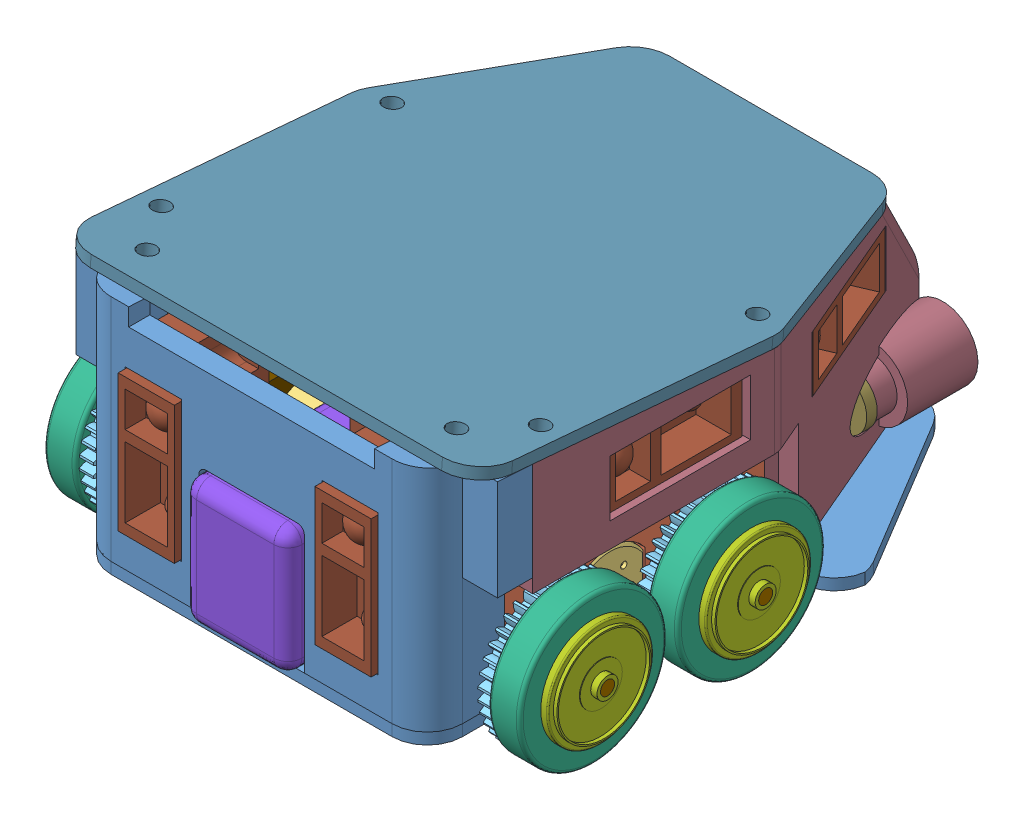
SolidWorks assembly Assem1, configuration Default. Lengths in mm.
Overall size (71.71 43.6 82.34).
50 component instances, 20 part files, 118 mates.
Components (placement in the parent):
- PCB-1: PCB [Default] at (41.0983 40.4465 84.0806) size (69.9 1.6 78)
- Ga DC2-2: Ga DC2 [Default] at (59.0983 47.0465 80.1639) size (17.4 13 40)
- N20 DC MOTOR Truc dai-1: N20 DC MOTOR Truc dai [Default] at (31.5883 47.126 80.164) x (0 -1 0) z (0 0 -1) size (12.48 22.6 10.65)
- N20 DC MOTOR Truc dai-2: N20 DC MOTOR Truc dai [Default] at (50.6983 47.1262 80.164) x (0 1 0) z (0 0 -1) size (12.48 22.6 10.65)
- gearT7-1: gearT7 [Default] at (13.7883 47.1262 80.164) x (1 0 0) z (0 0.945467 -0.325717) size (4.04 4.32 4.42)
- Spur gear 0.5M 38T-1: Spur gear 0.5M 38T [Default] at (11.7883 47.0465 91.4139) x (1 0 0) z (0 -0.781008 0.624521) size (5 19.95 20)
- Spur gear 0.5M 38T-2: Spur gear 0.5M 38T [Default] at (11.7883 47.0465 68.9139) x (1 0 0) z (0 0.630847 0.775907) size (5 19.95 20)
- Spur gear 0.5M 38T-3: Spur gear 0.5M 38T [Default] at (70.4983 47.0465 91.4139) x (-1 0 0) z (0 -0.877068 -0.480367) size (5 19.95 20)
- Spur gear 0.5M 38T-4: Spur gear 0.5M 38T [Default] at (70.4983 47.0465 68.9139) x (-1 0 0) z (0 -0.991708 0.12851) size (5 19.95 20)
- gearT7-2: gearT7 [Default] at (68.4983 47.1262 80.164) x (1 0 0) z (0 -0.999921 -0.012589) size (4.04 4.32 4.42)
- Lop banh xe-1: Lop banh xe [Default] at (69.7483 47.0465 91.4139) x (1 0 0) z (0 0.084338 0.996437) size (4.5 21 21)
- Mam banh xe-1: Mam banh xe [Default] at (71.9983 47.0465 91.4139) x (1 0 0) z (0 -0.016047 0.999871) size (2 15 15)
- Lop banh xe-2: Lop banh xe [Default] at (69.7483 47.0465 68.9139) size (4.5 21 21)
- Mam banh xe-2: Mam banh xe [Default] at (71.9983 47.0465 68.9139) size (2 15 15)
- Lop banh xe-3: Lop banh xe [Default] at (12.5383 47.0465 91.4139) x (-1 0 0) z (0 0.494346 -0.869265) size (4.5 21 21)
- Lop banh xe-4: Lop banh xe [Default] at (12.5383 47.0465 68.9139) x (-1 0 0) z (0 -0.036869 -0.99932) size (4.5 21 21)
- Mam banh xe-3: Mam banh xe [Default] at (10.2883 47.0465 91.4139) x (-1 0 0) z (0 -0.994328 -0.106358) size (2 15 15)
- Mam banh xe-4: Mam banh xe [Default] at (10.2883 47.0465 68.9139) x (-1 0 0) z (0 -0.999997 0.002571) size (2 15 15)
- Pin-1: Pin [Default] at (41.0983 51.0465 77.5088) x (0 0 -1) z (0 -1 0) size (62 15 18)
- Truc 2x20-1: Truc 2x20 [Default] at (15.7883 47.0465 91.4139) x (0 0 -1) z (-1 0 0) size (2 2 21)
- Truc 2x20-2: Truc 2x20 [Default] at (15.7883 47.0465 68.9139) x (0 0 -1) z (-1 0 0) size (2 2 21)
- Truc 2x20-3: Truc 2x20 [Default] at (66.4983 47.0465 68.9139) x (0 0 -1) z (-1 0 0) size (2 2 21)
- Truc 2x20-4: Truc 2x20 [Default] at (66.4983 47.0465 91.4139) x (0 0 -1) z (-1 0 0) size (2 2 21)
- MT6701-1: MT6701 [Default] at (33.5983 47.0465 68.6639) x (0 0 -1) z (-1 0 0) size (17 13 3.61)
- MT6701-2: MT6701 [Default] at (48.6883 47.0465 68.6639) x (0 0 1) z (1 0 0) size (17 13 3.61)
- SHARP GP2Y0A51SK0F-1: SHARP GP2Y0A51SK0F [Default] at (36.4032 80.517 54.6466) x (0.393919 0 0.919145) z (0 -1 0) size (27 14.5 13.5)
- SHARP GP2Y0A51SK0F-2: SHARP GP2Y0A51SK0F [Default] at (45.3065 80.517 55.7827) x (0.393919 0 -0.919145) z (0 -1 0) size (27 14.5 13.5)
- SHARP GP2Y0A51SK0F-5: SHARP GP2Y0A51SK0F [Default] at (41.4209 83.217 75.782) x (0 0 -1) z (0 -1 0) size (27 14.5 13.5)
- SHARP GP2Y0A51SK0F-6: SHARP GP2Y0A51SK0F [Default] at (40.7758 83.217 74.5459) x (0 0 1) z (0 -1 0) size (27 14.5 13.5)
- SHARP GP2Y0A51SK0F-7: SHARP GP2Y0A51SK0F [Default] at (72.7688 56.4285 77.8414) x (0 1 0) z (-1 0 0) size (27 14.5 13.5)
- SHARP GP2Y0A51SK0F-8: SHARP GP2Y0A51SK0F [Default] at (44.7688 56.4285 77.8414) x (0 1 0) z (-1 0 0) size (27 14.5 13.5)
- GP2Y0A41SK0F-1: GP2Y0A41SK0F [Default] at (41.0983 48.2965 40.8639) x (1 0 0) z (0 0 -1) size (44.5 18.9 13.5)
- Ga sensor 1-2: Ga sensor 1 [Default] at (41.0983 42.0465 78.6639) x (1 0 0) z (0 1 0) size (60 73 32)
- PCB2-1: PCB2 [Default] at (41.0983 71.6553 68.2662) x (1 0 0) z (0 0.085401 0.996347) size (60 1.6 72)
- Vong bi 2x5x2.5-1: Vong bi 2x5x2.5 [Default] at (62.2075 47.0465 68.9139) x (0 0.033218 -0.999448) z (1 0 0) size (5 5 2)
- Vong bi 2x5x2.5-2: Vong bi 2x5x2.5 [Default] at (67.2075 47.0465 68.9139) x (0 0 -1) z (1 0 0) size (5 5 2)
- Vong bi 2x5x2.5-3: Vong bi 2x5x2.5 [Default] at (67.2075 47.0465 91.4139) x (0 0.033218 -0.999448) z (1 0 0) size (5 5 2)
- Vong bi 2x5x2.5-4: Vong bi 2x5x2.5 [Default] at (62.2075 47.0465 91.4139) x (0 0.033218 -0.999448) z (1 0 0) size (5 5 2)
- Ga nam chamV3-1: Ga nam chamV3 [Default] at (58.7983 47.0465 68.9139) x (-1 0 0) z (0 -0.972709 -0.232028) size (4.8 7.5 7.5)
- Nam cham-1: Nam cham [Default] at (54.9983 47.0465 68.9139) x (0 -0.375893 -0.926663) z (1 0 0) size (4 4 2)
- Vong bi 2x5x2.5-5: Vong bi 2x5x2.5 [Default] at (24.2975 47.0465 68.9139) x (0 -0.968865 0.24759) z (1 0 0) size (5 5 2)
- Vong bi 2x5x2.5-6: Vong bi 2x5x2.5 [Default] at (24.2975 47.0465 91.4139) x (0 -0.501495 -0.865161) z (1 0 0) size (5 5 2)
- Vong bi 2x5x2.5-7: Vong bi 2x5x2.5 [Default] at (19.2975 47.0465 91.4139) x (0 -0.969455 0.245269) z (1 0 0) size (5 5 2)
- Vong bi 2x5x2.5-8: Vong bi 2x5x2.5 [Default] at (19.2975 47.0465 68.9139) x (0 -0.969455 0.245269) z (1 0 0) size (5 5 2)
- Ga nam chamV3-4: Ga nam chamV3 [Default] at (23.4883 47.0465 68.9139) x (1 0 0) z (0 -0.948341 -0.317251) size (4.8 7.5 7.5)
- Nam cham-3: Nam cham [Default] at (27.2883 47.0465 68.9139) x (0 -0.375893 -0.926663) z (1 0 0) size (4 4 2)
- Ga DC-3: Ga DC [Default] at (16.1883 47.0465 80.1639) size (17.4 13 40)
- Ga sensor sau-1: Ga sensor sau [Default] at (41.0983 58.3665 106.1639) size (60 32.64 11)
- Kep truc-1: Kep truc [Default] at (55.9983 47.0465 91.4139) x (0 0.202703 -0.97924) z (1 0 0) size (6 6 2.8)
- Kep truc-2: Kep truc [Default] at (23.4883 47.0465 91.4139) x (0 -0.00317 -0.999995) z (1 0 0) size (6 6 2.8)
Mates (geometry in assembly coordinates):
- Coincident1: coincident anti-aligned: plane of PCB-1 through (41.0983 42.0465 84.0806) normal (0 1 0); plane of Ga DC2-2 through (66.0983 42.0465 80.1639) normal (0 -1 0)
- Coincident4: coincident aligned: plane of Ga DC2-2 through (66.0983 47.0465 80.1639) normal (1 0 0); plane of PCB-1 through (66.0983 42.0465 106.1639) normal (1 0 0)
- Coincident9: coincident aligned: plane of Ga DC2-2 through (66.0983 47.0465 80.1639) normal (1 0 0); plane of N20 DC MOTOR Truc dai-2 through (66.0983 47.0993 80.195) normal (1 0 0)
- Concentric3: concentric anti-aligned: cylinder of N20 DC MOTOR Truc dai-1 through (10.7883 47.126 80.164) axis (1 0 0) radius 0.5; cylinder of gearT7-1 through (15.7883 47.1262 80.164) axis (-1 0 0) radius 0.5
- Distance1: distance = 1 mm aligned: plane of gearT7-1 through (11.7883 47.1262 80.164) normal (-1 0 0); plane of N20 DC MOTOR Truc dai-1 through (10.7883 47.126 80.164) normal (-1 0 0)
- Coincident13: coincident aligned: plane of gearT7-1 through (11.7883 47.1262 80.164) normal (-1 0 0); plane of Spur gear 0.5M 38T-1 through (11.7883 47.0465 91.4139) normal (-1 0 0)
- Coincident14: coincident aligned: plane of gearT7-1 through (11.7883 47.1262 80.164) normal (-1 0 0); plane of Spur gear 0.5M 38T-2 through (11.7883 47.0465 68.9139) normal (-1 0 0)
- Concentric7: concentric aligned: cylinder of N20 DC MOTOR Truc dai-2 through (71.4983 47.1262 80.164) axis (-1 0 0) radius 0.5; cylinder of gearT7-2 through (70.4983 47.1262 80.164) axis (-1 0 0) radius 0.5
- Concentric8: concentric anti-aligned: cylinder of Ga DC2-2 through (66.0983 47.0465 68.9139) axis (-1 0 0) radius 1; cylinder of Spur gear 0.5M 38T-4 through (65.4983 47.0465 68.9139) axis (1 0 0) radius 1
- Concentric9: concentric anti-aligned: cylinder of Ga DC2-2 through (66.0983 47.0465 91.4139) axis (-1 0 0) radius 1; cylinder of Spur gear 0.5M 38T-3 through (65.4983 47.0465 91.4139) axis (1 0 0) radius 1
- Coincident15: coincident aligned: plane of gearT7-2 through (70.4983 47.1262 80.164) normal (1 0 0); plane of Spur gear 0.5M 38T-3 through (70.4983 47.0465 91.4139) normal (1 0 0)
- Coincident16: coincident aligned: plane of gearT7-2 through (70.4983 47.1262 80.164) normal (1 0 0); plane of Spur gear 0.5M 38T-4 through (70.4983 47.0465 68.9139) normal (1 0 0)
- Distance2: distance = 1 mm aligned: plane of N20 DC MOTOR Truc dai-2 through (71.4983 47.1262 80.164) normal (1 0 0); plane of gearT7-2 through (70.4983 47.1262 80.164) normal (1 0 0)
- Concentric10: concentric aligned: cylinder of Lop banh xe-1 through (69.7483 47.0465 91.4139) axis (-1 0 0) radius 5.5; cylinder of Mam banh xe-1 through (71.9983 47.0465 91.4139) axis (-1 0 0) radius 1
- Concentric11: concentric anti-aligned: cylinder of Lop banh xe-1 through (69.7483 47.0465 91.4139) axis (-1 0 0) radius 5.5; cylinder of Spur gear 0.5M 38T-3 through (65.4983 47.0465 91.4139) axis (1 0 0) radius 1
- Concentric12: concentric anti-aligned: cylinder of Spur gear 0.5M 38T-4 through (65.4983 47.0465 68.9139) axis (1 0 0) radius 1; cylinder of Lop banh xe-2 through (69.7483 47.0465 68.9139) axis (-1 0 0) radius 5.5
- Concentric13: concentric anti-aligned: cylinder of Spur gear 0.5M 38T-4 through (65.4983 47.0465 68.9139) axis (1 0 0) radius 1; cylinder of Mam banh xe-2 through (71.9983 47.0465 68.9139) axis (-1 0 0) radius 1
- Coincident18: coincident anti-aligned: plane of Mam banh xe-2 through (74.9983 48.0465 68.9139) normal (-1 0 0); plane of Lop banh xe-2 through (74.9983 57.5465 68.9139) normal (1 0 0)
- Coincident19: coincident anti-aligned: plane of Lop banh xe-1 through (74.9983 57.5091 90.5284) normal (1 0 0); plane of Mam banh xe-1 through (74.9983 48.0464 91.43) normal (-1 0 0)
- Concentric14: concentric aligned: cylinder of Lop banh xe-4 through (12.5383 47.0465 68.9139) axis (1 0 0) radius 5.5; cylinder of Mam banh xe-4 through (10.2883 47.0465 68.9139) axis (1 0 0) radius 1
- Coincident20: coincident anti-aligned: plane of Lop banh xe-4 through (7.2883 57.5394 68.5268) normal (-1 0 0); plane of Mam banh xe-4 through (7.2883 47.044 67.9139) normal (1 0 0)
- Concentric15: concentric aligned: cylinder of Lop banh xe-3 through (12.5383 47.0465 91.4139) axis (1 0 0) radius 5.5; cylinder of Mam banh xe-3 through (10.2883 47.0465 91.4139) axis (1 0 0) radius 1
- Coincident21: coincident anti-aligned: plane of Mam banh xe-3 through (7.2883 47.1529 90.4196) normal (1 0 0); plane of Lop banh xe-3 through (7.2883 56.1738 96.6046) normal (-1 0 0)
- Concentric16: concentric anti-aligned: cylinder of Spur gear 0.5M 38T-1 through (16.7884 47.0465 91.4139) axis (-1 0 0) radius 1; cylinder of Mam banh xe-3 through (10.2883 47.0465 91.4139) axis (1 0 0) radius 1
- Concentric17: concentric anti-aligned: cylinder of Mam banh xe-4 through (10.2883 47.0465 68.9139) axis (1 0 0) radius 1; cylinder of Spur gear 0.5M 38T-2 through (16.7884 47.0465 68.9139) axis (-1 0 0) radius 1
- Coincident22: coincident anti-aligned: plane of Spur gear 0.5M 38T-1 through (11.7883 47.0465 91.4139) normal (-1 0 0); plane of Lop banh xe-3 through (11.7883 56.1738 96.6046) normal (1 0 0)
- Coincident23: coincident anti-aligned: plane of Lop banh xe-4 through (11.7883 57.5394 68.5268) normal (1 0 0); plane of Spur gear 0.5M 38T-2 through (11.7883 47.0465 68.9139) normal (-1 0 0)
- Coincident24: coincident anti-aligned: plane of Lop banh xe-1 through (70.4983 57.5091 90.5284) normal (-1 0 0); plane of Spur gear 0.5M 38T-3 through (70.4983 47.0465 91.4139) normal (1 0 0)
- Coincident25: coincident anti-aligned: plane of Spur gear 0.5M 38T-4 through (70.4983 47.0465 68.9139) normal (1 0 0); plane of Lop banh xe-2 through (70.4983 57.5465 68.9139) normal (-1 0 0)
- Width1: width anti-aligned: plane of Pin-1 through (33.5983 51.0465 77.5088) normal (-1 0 0); plane of PCB-1 through (48.5983 51.0465 77.5088) normal (1 0 0); plane of Pin-1 through (66.0983 42.0465 106.1639) normal (1 0 0); plane of PCB-1 through (16.0983 42.0465 106.1639) normal (-1 0 0)
- Concentric18: concentric aligned: cylinder of Mam banh xe-4 through (10.2883 47.0465 68.9139) axis (1 0 0) radius 1; cylinder of Truc 2x20-2 through (5.2883 47.0465 68.9139) axis (1 0 0) radius 1
- Concentric19: concentric aligned: cylinder of Mam banh xe-3 through (10.2883 47.0465 91.4139) axis (1 0 0) radius 1; cylinder of Truc 2x20-1 through (5.2883 47.0465 91.4139) axis (1 0 0) radius 1
- Coincident28: coincident aligned: plane of Mam banh xe-3 through (5.2883 47.2061 89.9224) normal (-1 0 0); plane of Truc 2x20-1 through (5.2883 47.0465 91.4139) normal (-1 0 0)
- Coincident29: coincident aligned: plane of Mam banh xe-4 through (5.2883 47.0427 67.4139) normal (-1 0 0); plane of Truc 2x20-2 through (5.2883 47.0465 68.9139) normal (-1 0 0)
- Concentric20: concentric anti-aligned: cylinder of Mam banh xe-1 through (71.9983 47.0465 91.4139) axis (-1 0 0) radius 1; cylinder of Truc 2x20-4 through (55.9983 47.0465 91.4139) axis (1 0 0) radius 1
- Coincident30: coincident aligned: plane of Mam banh xe-1 through (76.9983 48.5463 91.438) normal (1 0 0); plane of Truc 2x20-4 through (76.9983 47.0465 91.4139) normal (1 0 0)
- Concentric21: concentric anti-aligned: cylinder of Mam banh xe-2 through (71.9983 47.0465 68.9139) axis (-1 0 0) radius 1; cylinder of Truc 2x20-3 through (55.9983 47.0465 68.9139) axis (1 0 0) radius 1
- Coincident31: coincident aligned: plane of Mam banh xe-2 through (76.9983 48.5465 68.9139) normal (1 0 0); plane of Truc 2x20-3 through (76.9983 47.0465 68.9139) normal (1 0 0)
- Parallel2: parallel anti-aligned: plane of Truc 2x20-1 through (26.2883 47.0465 91.4139) normal (1 0 0); plane of MT6701-1 through (29.9883 47.0465 68.6639) normal (-1 0 0)
- Coincident35: coincident anti-aligned: plane of Pin-1 through (33.5983 51.0465 77.5088) normal (-1 0 0); plane of MT6701-1 through (33.5983 47.0465 68.6639) normal (1 0 0)
- Parallel3: parallel anti-aligned: plane of Truc 2x20-4 through (55.9983 47.0465 91.4139) normal (-1 0 0); plane of MT6701-2 through (52.2983 47.0465 68.6639) normal (1 0 0)
- Width3: width anti-aligned: plane of GP2Y0A41SK0F-1 through (26.3483 52.4965 40.8639) normal (0 1 0); plane of Ga sensor 1-2 through (55.8483 44.0965 40.8639) normal (0 -1 0); plane of GP2Y0A41SK0F-1 through (26.0983 52.5465 51.1639) normal (0 -1 0); plane of Ga sensor 1-2 through (26.0983 44.0465 51.1639) normal (0 1 0)
- Width4: width anti-aligned: plane of GP2Y0A41SK0F-1 through (55.8483 52.4965 40.8639) normal (1 0 0); plane of Ga sensor 1-2 through (26.3483 44.0965 40.8639) normal (-1 0 0); plane of GP2Y0A41SK0F-1 through (56.0983 74.0465 51.1639) normal (-1 0 0); plane of Ga sensor 1-2 through (26.0983 74.0465 51.1639) normal (1 0 0)
- Coincident76: coincident anti-aligned: plane of GP2Y0A41SK0F-1 through (31.1983 53.6465 33.6639) normal (0 0 -1); plane of Ga sensor 1-2 through (59.4683 48.2965 33.6639) normal (0 0 1)
- Coincident77: coincident anti-aligned: plane of SHARP GP2Y0A51SK0F-6 through (66.0983 65.5465 75.1639) normal (1 0 0); plane of Ga sensor 1-2 through (66.0983 42.0465 78.6639) normal (-1 0 0)
- Width5: width anti-aligned: plane of Ga sensor 1-2 through (-29.0638 74.0465 65.1639) normal (0 0 1); plane of SHARP GP2Y0A51SK0F-6 through (-29.0638 74.0465 85.1639) normal (0 0 -1); plane of Ga sensor 1-2 through (70.0983 69.5465 84.9139) normal (0 0 1); plane of SHARP GP2Y0A51SK0F-6 through (70.0983 61.5465 65.4139) normal (0 0 -1)
- Width6: width anti-aligned: plane of Ga sensor 1-2 through (-29.0638 74.0465 65.1639) normal (0 0 1); plane of SHARP GP2Y0A51SK0F-5 through (-29.0638 74.0465 85.1639) normal (0 0 -1); plane of Ga sensor 1-2 through (12.0983 61.5465 84.9139) normal (0 0 1); plane of SHARP GP2Y0A51SK0F-5 through (12.0983 69.5465 65.4139) normal (0 0 -1)
- Coincident81: coincident anti-aligned: plane of SHARP GP2Y0A51SK0F-5 through (16.0983 65.5465 75.1639) normal (-1 0 0); plane of Ga sensor 1-2 through (16.0983 42.0465 78.6639) normal (1 0 0)
- Coincident82: coincident anti-aligned: plane of PCB-1 through (41.0983 42.0465 84.0806) normal (0 1 0); plane of Ga sensor 1-2 through (41.0983 42.0465 78.6639) normal (0 -1 0)
- Coincident85: coincident aligned: plane of SHARP GP2Y0A51SK0F-2 through (18.5983 62.8465 43.6639) normal (-0.919145 0 -0.393919); plane of Ga sensor 1-2 through (11.0983 74.0465 61.1639) normal (-0.919145 0 -0.393919)
- Width7: width aligned: plane of SHARP GP2Y0A51SK0F-2 through (14.7576 58.8465 52.6256) normal (-0.393919 0 0.919145); plane of Ga sensor 1-2 through (22.439 66.8465 34.7023) normal (0.393919 0 -0.919145); plane of SHARP GP2Y0A51SK0F-2 through (36.3247 74.0465 40.3813) normal (-0.393919 0 0.919145); plane of Ga sensor 1-2 through (28.4463 74.0465 58.7642) normal (0.393919 0 -0.919145)
- Width9: width aligned: plane of SHARP GP2Y0A51SK0F-1 through (67.439 66.8465 52.6256) normal (0.393919 0 0.919145); plane of Ga sensor 1-2 through (59.7576 58.8465 34.7023) normal (-0.393919 0 -0.919145); plane of SHARP GP2Y0A51SK0F-1 through (45.872 74.0465 40.3813) normal (0.393919 0 0.919145); plane of Ga sensor 1-2 through (53.7504 74.0465 58.7642) normal (-0.393919 0 -0.919145)
- Coincident89: coincident anti-aligned: plane of SHARP GP2Y0A51SK0F-6 through (70.0983 61.5465 84.9139) normal (0 -1 0); plane of Ga sensor 1-2 through (-29.0638 61.5465 96.1639) normal (0 1 0)
- Coincident90: coincident anti-aligned: plane of SHARP GP2Y0A51SK0F-5 through (12.0983 61.5465 65.4139) normal (0 -1 0); plane of Ga sensor 1-2 through (-29.0638 61.5465 96.1639) normal (0 1 0)
- Width11: width anti-aligned: plane of SHARP GP2Y0A51SK0F-1 through (59.7576 66.8465 34.7023) normal (0 1 0); plane of Ga sensor 1-2 through (67.439 58.8465 52.6256) normal (0 -1 0); plane of SHARP GP2Y0A51SK0F-1 through (42.3112 66.8465 32.0727) normal (0 -1 0); plane of Ga sensor 1-2 through (42.3112 58.8465 32.0727) normal (0 1 0)
- Coincident91: coincident anti-aligned: plane of Ga sensor 1-2 through (10.0983 68.0465 26.1639) normal (0 0.996347 -0.085401); plane of PCB2-1 through (41.0983 71.6553 68.2662) normal (0 -0.996347 0.085401)
- Coincident93: coincident aligned: line of Ga sensor 1-2 through (11.0983 74.0465 96.1639) axis (0 -0.085401 -0.996347); line of PCB2-1 through (11.0983 74.3027 99.153) axis (0 -0.085401 -0.996347)
- Coincident100: coincident anti-aligned: plane of PCB-1 through (41.0983 42.0465 84.0806) normal (0 1 0); plane of Pin-1 through (48.5983 42.0465 108.5088) normal (0 -1 0)
- Concentric23: concentric aligned: cylinder of Ga DC2-2 through (66.0983 47.0465 80.1639) axis (-1 0 0) radius 6.25; cylinder of N20 DC MOTOR Truc dai-2 through (65.5983 47.0465 80.1639) axis (-1 0 0) radius 5.9205
- Coincident102: coincident anti-aligned: plane of Ga DC2-2 through (66.0983 47.0465 75.1639) normal (0 0 1); plane of N20 DC MOTOR Truc dai-2 through (65.5983 50.3762 75.164) normal (0 0 -1)
- Coincident105: coincident anti-aligned: plane of PCB-1 through (41.0983 42.0465 84.0806) normal (0 1 0); plane of MT6701-1 through (31.5983 42.0465 77.1639) normal (0 -1 0)
- Concentric24: concentric anti-aligned: cylinder of Ga DC2-2 through (61.0983 47.0465 68.9139) axis (-1 0 0) radius 2.5; cylinder of Vong bi 2x5x2.5-1 through (62.2075 47.0465 68.9139) axis (1 0 0) radius 2.5
- Concentric25: concentric anti-aligned: cylinder of Ga DC2-2 through (61.0983 47.0465 68.9139) axis (-1 0 0) radius 2.5; cylinder of Vong bi 2x5x2.5-2 through (67.2075 47.0465 68.9139) axis (1 0 0) radius 2.5
- Coincident106: coincident aligned: plane of Ga DC2-2 through (59.0983 47.0465 80.1639) normal (-1 0 0); plane of Vong bi 2x5x2.5-1 through (59.0983 49.5452 68.997) normal (-1 0 0)
- Coincident107: coincident aligned: plane of Ga DC2-2 through (66.0983 47.0465 80.1639) normal (1 0 0); plane of Vong bi 2x5x2.5-2 through (66.0983 49.0465 68.9139) normal (1 0 0)
- Concentric26: concentric aligned: cylinder of Truc 2x20-4 through (55.9983 47.0465 91.4139) axis (1 0 0) radius 1; cylinder of Vong bi 2x5x2.5-4 through (62.2075 47.0465 91.4139) axis (1 0 0) radius 1
- Coincident108: coincident aligned: plane of Ga DC2-2 through (59.0983 47.0465 80.1639) normal (-1 0 0); plane of Vong bi 2x5x2.5-4 through (59.0983 49.5452 91.497) normal (-1 0 0)
- Concentric27: concentric aligned: cylinder of Truc 2x20-4 through (55.9983 47.0465 91.4139) axis (1 0 0) radius 1; cylinder of Vong bi 2x5x2.5-3 through (67.2075 47.0465 91.4139) axis (1 0 0) radius 1
- Coincident109: coincident aligned: plane of Ga DC2-2 through (66.0983 47.0465 80.1639) normal (1 0 0); plane of Vong bi 2x5x2.5-3 through (66.0983 49.0454 91.4804) normal (1 0 0)
- Concentric28: concentric aligned: cylinder of Truc 2x20-3 through (55.9983 47.0465 68.9139) axis (1 0 0) radius 1; cylinder of Ga nam chamV3-1 through (58.7983 47.0465 68.9139) axis (1 0 0) radius 1
- Coincident110: coincident aligned: plane of Truc 2x20-3 through (55.9983 47.0465 68.9139) normal (-1 0 0); plane of Ga nam chamV3-1 through (55.9983 47.2786 67.9412) normal (-1 0 0)
- Concentric30: concentric anti-aligned: cylinder of Ga nam chamV3-1 through (58.7983 47.0465 68.9139) axis (1 0 0) radius 2.05; cylinder of Nam cham-1 through (55.9983 47.0465 68.9139) axis (-1 0 0) radius 2
- Coincident112: coincident aligned: plane of Ga nam chamV3-1 through (53.9983 47.5222 66.9199) normal (-1 0 0); plane of Nam cham-1 through (53.9983 47.0465 68.9139) normal (-1 0 0)
- Concentric32: concentric aligned: cylinder of Truc 2x20-2 through (5.2883 47.0465 68.9139) axis (1 0 0) radius 1; cylinder of Vong bi 2x5x2.5-5 through (24.2975 47.0465 68.9139) axis (1 0 0) radius 1
- Concentric33: concentric aligned: cylinder of Truc 2x20-1 through (5.2883 47.0465 91.4139) axis (1 0 0) radius 1; cylinder of Vong bi 2x5x2.5-6 through (24.2975 47.0465 91.4139) axis (1 0 0) radius 1
- Concentric34: concentric aligned: cylinder of Truc 2x20-2 through (5.2883 47.0465 68.9139) axis (1 0 0) radius 1; cylinder of Vong bi 2x5x2.5-8 through (19.2975 47.0465 68.9139) axis (1 0 0) radius 1
- Concentric35: concentric aligned: cylinder of Truc 2x20-1 through (5.2883 47.0465 91.4139) axis (1 0 0) radius 1; cylinder of Vong bi 2x5x2.5-7 through (19.2975 47.0465 91.4139) axis (1 0 0) radius 1
- Concentric37: concentric anti-aligned: cylinder of Truc 2x20-2 through (5.2883 47.0465 68.9139) axis (1 0 0) radius 1; cylinder of Ga nam chamV3-4 through (23.4883 47.0465 68.9139) axis (-1 0 0) radius 1
- Coincident119: coincident aligned: plane of Truc 2x20-2 through (26.2883 47.0465 68.9139) normal (1 0 0); plane of Ga nam chamV3-4 through (26.2883 46.7293 69.8623) normal (1 0 0)
- Concentric39: concentric aligned: cylinder of Ga nam chamV3-4 through (23.4883 47.0465 68.9139) axis (-1 0 0) radius 2.05; cylinder of Nam cham-3 through (28.2883 47.0465 68.9139) axis (-1 0 0) radius 2
- Coincident121: coincident aligned: plane of Ga nam chamV3-4 through (28.2883 46.3962 70.858) normal (1 0 0); plane of Nam cham-3 through (28.2883 47.0465 68.9139) normal (1 0 0)
- Coincident122: coincident anti-aligned: plane of PCB-1 through (41.0983 42.0465 84.0806) normal (0 1 0); plane of MT6701-2 through (50.6883 42.0465 60.1639) normal (0 -1 0)
- Coincident123: coincident anti-aligned: plane of Ga DC2-2 through (50.2983 47.0465 80.1639) normal (-1 0 0); plane of MT6701-2 through (50.2983 47.0465 68.6639) normal (1 0 0)
- Coincident124: coincident anti-aligned: plane of Ga DC2-2 through (50.2983 55.0465 60.1639) normal (0 0 1); plane of MT6701-2 through (50.2983 53.0465 60.1639) normal (0 0 -1)
- Concentric40: concentric anti-aligned: cylinder of N20 DC MOTOR Truc dai-1 through (16.6883 47.0465 80.1639) axis (1 0 0) radius 5.9205; cylinder of Ga DC-3 through (23.1883 47.0465 80.1639) axis (-1 0 0) radius 6.1
- Parallel5: parallel anti-aligned: plane of N20 DC MOTOR Truc dai-1 through (16.6883 43.876 75.164) normal (0 0 -1); plane of Ga DC-3 through (23.1883 47.0465 75.1639) normal (0 0 1)
- Concentric41: concentric anti-aligned: cylinder of Vong bi 2x5x2.5-8 through (19.2975 47.0465 68.9139) axis (1 0 0) radius 2.5; cylinder of Ga DC-3 through (18.1883 47.0465 68.9139) axis (-1 0 0) radius 2.5
- Coincident126: coincident anti-aligned: circle of Vong bi 2x5x2.5-8; plane of Ga DC-3 through (16.1883 47.0465 80.1639) normal (-1 0 0)
- Coincident127: coincident aligned: plane of Vong bi 2x5x2.5-5 through (23.1883 46.5514 66.9762) normal (1 0 0); plane of Ga DC-3 through (23.1883 47.0465 80.1639) normal (1 0 0)
- Coincident128: coincident aligned: plane of N20 DC MOTOR Truc dai-1 through (16.1883 47.1528 80.195) normal (-1 0 0); plane of Ga DC-3 through (16.1883 47.0465 80.1639) normal (-1 0 0)
- Concentric42: concentric anti-aligned: cylinder of Vong bi 2x5x2.5-7 through (19.2975 47.0465 91.4139) axis (1 0 0) radius 2.5; cylinder of Ga DC-3 through (18.1883 47.0465 91.4139) axis (-1 0 0) radius 2.5
- Coincident129: coincident aligned: plane of Vong bi 2x5x2.5-6 through (23.1883 48.7769 90.4109) normal (1 0 0); plane of Ga DC-3 through (23.1883 47.0465 80.1639) normal (1 0 0)
- Coincident130: coincident aligned: plane of Vong bi 2x5x2.5-7 through (16.1883 46.4334 88.9903) normal (-1 0 0); plane of Ga DC-3 through (16.1883 47.0465 80.1639) normal (-1 0 0)
- Coincident131: coincident anti-aligned: plane of MT6701-1 through (31.9883 53.0465 60.1639) normal (0 0 -1); plane of Ga DC-3 through (31.9883 81.5562 60.1639) normal (0 0 1)
- Coincident132: coincident anti-aligned: plane of MT6701-1 through (31.9883 47.0465 68.6639) normal (-1 0 0); plane of Ga DC-3 through (31.9883 47.0465 80.1639) normal (1 0 0)
- Coincident134: coincident aligned: plane of MT6701-1 through (31.5983 42.0465 77.1639) normal (0 -1 0); plane of Ga DC-3 through (23.1883 42.0465 80.1639) normal (0 -1 0)
- Coincident135: coincident anti-aligned: plane of PCB-1 through (6.0983 42.0465 58.1639) normal (0 0 1); plane of Ga DC-3 through (23.1883 24.3898 58.1639) normal (0 0 -1)
- Width12: width aligned: plane of Ga sensor 1-2 through (11.0983 74.0465 61.1639) normal (-0.919145 0 -0.393919); plane of PCB-1 through (56.0983 74.0465 26.1639) normal (0.919145 0 -0.393919); plane of Ga sensor 1-2 through (21.0983 42.0465 28.1639) normal (-0.857493 0 -0.514496); plane of PCB-1 through (61.0983 42.0465 28.1639) normal (0.857493 0 -0.514496)
- Coincident136: coincident anti-aligned: plane of Ga sensor 1-2 through (-29.0638 74.0465 58.1639) normal (0 0 1); plane of Ga DC-3 through (23.1883 24.3898 58.1639) normal (0 0 -1)
- Concentric43: concentric aligned: cylinder of Ga sensor 1-2 through (14.0983 63.7415 93.0326) axis (0 0.996347 -0.085401) radius 1.1; cylinder of PCB2-1 through (14.0983 72.8082 92.2554) axis (0 0.996347 -0.085401) radius 1.25
- Coincident137: coincident aligned: plane of Ga DC2-2 through (66.0983 47.0465 95.1639) normal (0 0 1); plane of Ga DC-3 through (23.1883 47.0465 95.1639) normal (0 0 1)
- Coincident140: coincident aligned: plane of SHARP GP2Y0A51SK0F-7 through (60.5983 70.5465 95.1639) normal (0 1 0); plane of SHARP GP2Y0A51SK0F-8 through (32.5983 70.5465 95.1639) normal (0 1 0)
- Width13: width anti-aligned: plane of SHARP GP2Y0A51SK0F-7 through (59.0983 47.2965 107.1639) normal (1 0 0); plane of Ga sensor sau-1 through (51.0983 66.7965 107.1639) normal (-1 0 0); plane of SHARP GP2Y0A51SK0F-7 through (59.0983 47.0465 102.1639) normal (-1 0 0); plane of Ga sensor sau-1 through (51.0983 47.0465 102.1639) normal (1 0 0)
- Width14: width anti-aligned: plane of SHARP GP2Y0A51SK0F-7 through (59.0983 66.7965 107.1639) normal (0 1 0); plane of Ga sensor sau-1 through (51.0983 47.2965 107.1639) normal (0 -1 0); plane of SHARP GP2Y0A51SK0F-7 through (51.0983 67.0465 102.1639) normal (0 -1 0); plane of Ga sensor sau-1 through (51.0983 47.0465 102.1639) normal (0 1 0)
- Width15: width anti-aligned: plane of Ga sensor sau-1 through (23.0983 47.0465 102.1639) normal (1 0 0); plane of SHARP GP2Y0A51SK0F-8 through (31.0983 47.0465 102.1639) normal (-1 0 0); plane of Ga sensor sau-1 through (23.0983 66.7965 107.1639) normal (-1 0 0); plane of SHARP GP2Y0A51SK0F-8 through (31.0983 47.2965 107.1639) normal (1 0 0)
- Coincident146: coincident anti-aligned: plane of SHARP GP2Y0A51SK0F-7 through (55.0983 57.0465 103.1639) normal (0 0 1); plane of Ga sensor sau-1 through (61.0983 74.6865 103.1639) normal (0 0 -1)
- Coincident147: coincident anti-aligned: plane of PCB-1 through (41.0983 42.0465 84.0806) normal (0 1 0); plane of Ga sensor sau-1 through (41.0983 42.0465 106.1639) normal (0 -1 0)
- Coincident148: coincident anti-aligned: plane of SHARP GP2Y0A51SK0F-8 through (27.0983 57.0465 103.1639) normal (0 0 1); plane of Ga sensor sau-1 through (61.0983 74.6865 103.1639) normal (0 0 -1)
- Coincident150: coincident anti-aligned: plane of Ga DC2-2 through (66.0983 47.0465 95.1639) normal (0 0 1); plane of Ga sensor sau-1 through (66.0983 74.6865 95.1639) normal (0 0 -1)
- Coincident151: coincident anti-aligned: plane of Pin-1 through (33.5983 51.0465 77.5088) normal (-1 0 0); plane of Ga sensor sau-1 through (33.5983 60.0465 102.1639) normal (1 0 0)
- GearMate2: gear = 2.5 : 17.748 mm: cylinder of Spur gear 0.5M 38T-2 through (13.7883 47.0465 68.9139) axis (-1 0 0) radius 8.874; cylinder of gearT7-1 through (11.7883 47.1262 80.164) axis (1 0 0) radius 1.25
- GearMate3: gear = 2.5 : 17.748 mm: cylinder of Spur gear 0.5M 38T-1 through (13.7883 47.0465 91.4139) axis (-1 0 0) radius 8.874; cylinder of gearT7-1 through (11.7883 47.1262 80.164) axis (1 0 0) radius 1.25
- Coincident152: coincident anti-aligned: plane of SHARP GP2Y0A51SK0F-2 through (22.439 58.8465 34.7023) normal (0 -1 0); plane of Ga sensor 1-2 through (24.8855 58.8465 67.0727) normal (0 1 0)
- Coincident153: coincident anti-aligned: plane of SHARP GP2Y0A51SK0F-1 through (59.9218 62.8465 45.2396) normal (0.919145 0 -0.393919); plane of Ga sensor 1-2 through (69.1028 42.0465 66.662) normal (-0.919145 0 0.393919)
- Concentric44: concentric anti-aligned: cylinder of Truc 2x20-4 through (55.9983 47.0465 91.4139) axis (1 0 0) radius 1; cylinder of Kep truc-1 through (58.7983 47.0465 91.4139) axis (-1 0 0) radius 1
- Concentric45: concentric anti-aligned: cylinder of Truc 2x20-1 through (5.2883 47.0465 91.4139) axis (1 0 0) radius 1; cylinder of Kep truc-2 through (26.2883 47.0465 91.4139) axis (-1 0 0) radius 1
- Coincident154: coincident aligned: plane of Truc 2x20-4 through (55.9983 47.0465 91.4139) normal (-1 0 0); plane of Kep truc-1 through (55.9983 47.0465 91.4139) normal (-1 0 0)
- Coincident155: coincident aligned: plane of Truc 2x20-1 through (26.2883 47.0465 91.4139) normal (1 0 0); plane of Kep truc-2 through (26.2883 47.0465 91.4139) normal (1 0 0)
